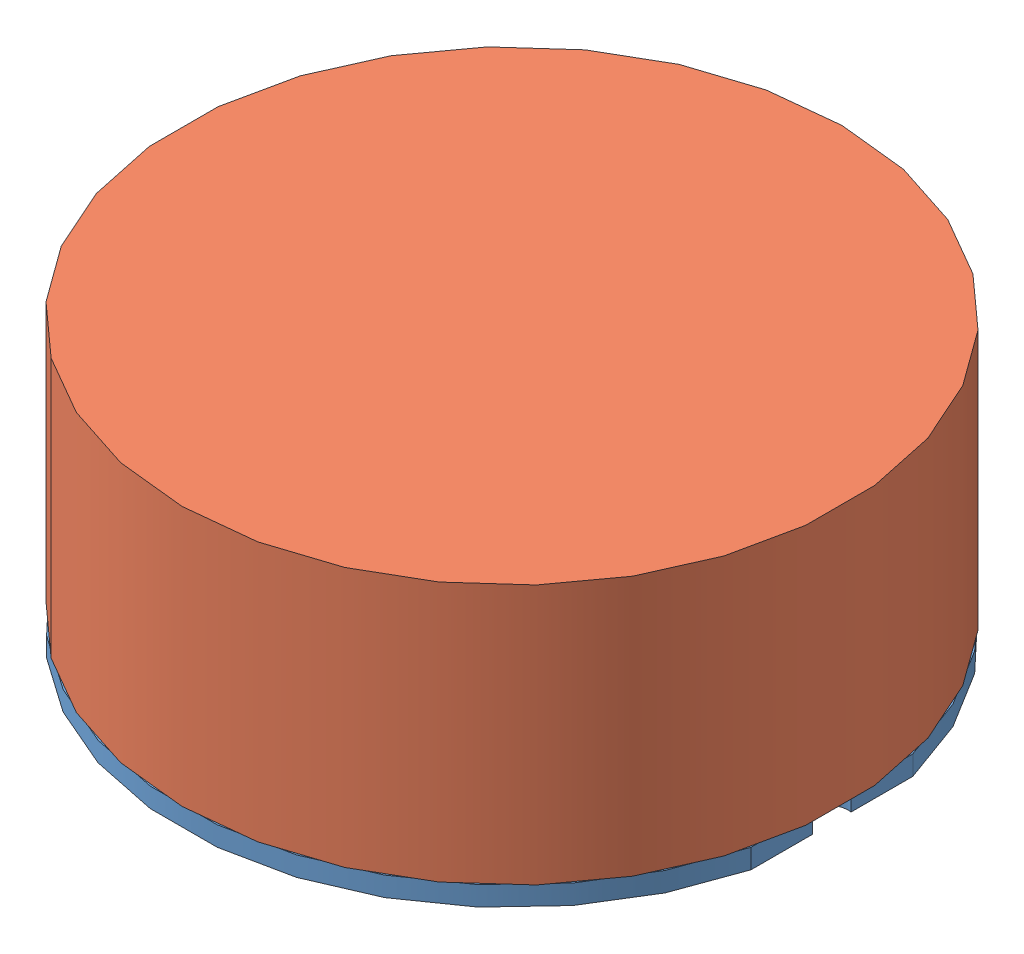
SolidWorks assembly Assem1, configuration Default. Lengths in mm.
Overall size (50.8 21.5 50.8).
2 component instances, 2 part files, 2 mates.
Components (placement in the parent):
- circuit_board-1: circuit_board [Default] at origin size (49.25 1.5 50.8)
- circuit_parts-1: circuit_parts [Default] at (0 1.5 0) size (50.8 20 50.8)
Mates (geometry in assembly coordinates):
- 同心円1: concentric: cylinder of circuit_board-1 through (0 1.5 0) axis (0 -1 0) radius 25.4; cylinder of circuit_parts-1 through (0 14.7717 0) axis (0 -1 0) radius 25.4
- 一致1: coincident anti-aligned: plane of circuit_board-1 through (0 1.5 0) normal (0 1 0); plane of circuit_parts-1 through (0 1.5 0) normal (0 -1 0)
